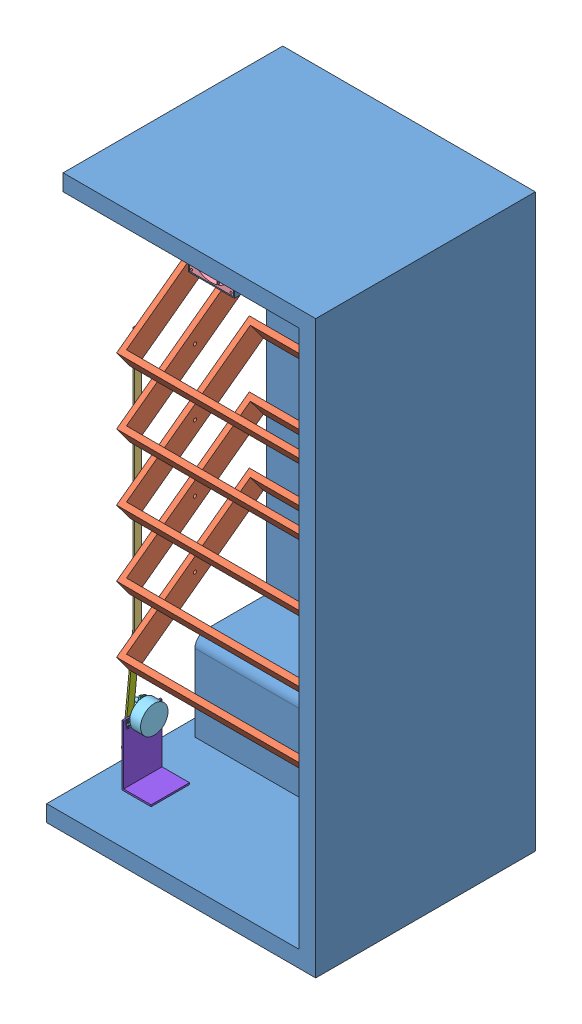
SolidWorks assembly lapgheptu2, configuration Default. Lengths in mm.
Overall size (490 1040 400).
12 component instances, 8 part files, 29 mates.
Components (placement in the parent):
- thungtu2-1: thungtu2 [Default] at (159.6175 470.8921 967.7159) size (490 1040 400)
- khaylat-1: khaylat [Default] at (164.6175 734.784 1115.8614) x (1 0 0) z (0 -0.592723 0.805406) size (410 40 300)
- khaylat-2: khaylat [Default] at (164.6175 614.784 1115.8614) x (1 0 0) z (0 -0.592723 0.805406) size (410 40 300)
- khaylat-3: khaylat [Default] at (164.6175 494.784 1115.8614) x (1 0 0) z (0 -0.592723 0.805406) size (410 40 300)
- khaylat-4: khaylat [Default] at (164.6175 374.784 1115.8614) x (1 0 0) z (0 -0.592723 0.805406) size (410 40 300)
- khaylat-5: khaylat [Default] at (164.6175 254.784 1115.8614) x (1 0 0) z (0 -0.592723 0.805406) size (410 40 300)
- caylap-1: caylap [Default] at (-43.3825 445.6926 1216.3106) size (3 500 12)
- khungquat-1: khungquat [Default] at (144.6175 920.8921 1242.7159) size (80 80 25)
- dongco-1: dongco [Default] at (-15.3825 85.8921 1211.7159) x (-1 0 0) z (0 0 -1) size (35 50 63.71)
- caylapdc-1: caylapdc [Default] at (-37.3825 67.8015 1223.1181) x (-1 0 0) z (0 -0.325777 -0.945447) size (13 90 12)
- caynoi-1: caynoi [Default] at (-45.3825 121.1472 1225.0896) x (1 0 0) z (0 0.103283 0.994652) size (3 190 12)
- gadedc-1: gadedc [Default] at (-35.3825 35.8921 1212.5572) x (0 0 1) z (-1 0 0) size (70 110 53)
Mates (geometry in assembly coordinates):
- Concentric1: concentric: cylinder of thungtu2-1 through (324.6175 750.8921 1127.7159) axis (1 0 0) radius 3; cylinder of ? through (-43.8678 750.8921 1127.7159) axis (1 0 0) radius 3
- Distance1: distance = 10 mm: plane of assembly; plane of assembly; plane of khaylat-1 through (364.6175 678.0918 1260.3813) normal (1 0 0); plane of thungtu2-1 through (374.6175 -19.1079 1337.7159) normal (-1 0 0)
- Concentric2: concentric: cylinder of thungtu2-1 through (324.6175 630.8921 1127.7159) axis (1 0 0) radius 3; cylinder of ? through (-43.8678 630.8921 1127.7159) axis (1 0 0) radius 3
- Distance2: distance = 10 mm: plane of assembly; plane of assembly; plane of khaylat-2 through (364.6175 558.0918 1260.3813) normal (1 0 0); plane of thungtu2-1 through (374.6175 -19.1079 1337.7159) normal (-1 0 0)
- Concentric3: concentric: cylinder of thungtu2-1 through (324.6175 510.8921 1127.7159) axis (1 0 0) radius 3; cylinder of ? through (-43.8678 510.8921 1127.7159) axis (1 0 0) radius 3
- Distance3: distance = 10 mm: plane of assembly; plane of assembly; plane of khaylat-3 through (364.6175 438.0918 1260.3813) normal (1 0 0); plane of thungtu2-1 through (374.6175 -19.1079 1337.7159) normal (-1 0 0)
- Concentric4: concentric: cylinder of thungtu2-1 through (324.6175 390.8921 1127.7159) axis (1 0 0) radius 3; cylinder of ? through (-43.8678 390.8921 1127.7159) axis (1 0 0) radius 3
- Distance4: distance = 10 mm: plane of assembly; plane of assembly; plane of khaylat-4 through (364.6175 318.0918 1260.3813) normal (1 0 0); plane of thungtu2-1 through (374.6175 -19.1079 1337.7159) normal (-1 0 0)
- Concentric5: concentric: cylinder of thungtu2-1 through (324.6175 270.8921 1127.7159) axis (1 0 0) radius 3; cylinder of ? through (-43.8678 270.8921 1127.7159) axis (1 0 0) radius 3
- Distance5: distance = 10 mm: plane of assembly; plane of assembly; plane of khaylat-5 through (364.6175 198.0918 1260.3813) normal (1 0 0); plane of thungtu2-1 through (374.6175 -19.1079 1337.7159) normal (-1 0 0)
- Coincident9: coincident: circle of ?; cylinder of ? through (-31.8972 718.3402 1253.5744) axis (-1 0 0) radius 3
- Distance6: distance = 5 mm: plane of assembly; plane of assembly; plane of khaylat-1 through (-35.3825 678.0918 1260.3813) normal (-1 0 0); plane of caylap-1 through (-40.3825 445.6926 1216.3106) normal (1 0 0)
- Coincident11: coincident: circle of ?; cylinder of ? through (-31.8972 598.3402 1253.5744) axis (-1 0 0) radius 3
- Coincident12: coincident: circle of ?; cylinder of ? through (-31.8972 478.3402 1253.5744) axis (-1 0 0) radius 3
- Coincident13: coincident: circle of ?; cylinder of ? through (-31.8972 358.3402 1253.5744) axis (-1 0 0) radius 3
- Coincident14: coincident: circle of ?; cylinder of ? through (-31.8972 238.3402 1253.5744) axis (-1 0 0) radius 3
- Coincident15: coincident: plane of assembly; plane of assembly; plane of thungtu2-1 through (-55.3825 960.8921 1337.7159) normal (0 -1 0); plane of khungquat-1 through (104.6175 960.8921 1263.7159) normal (0 1 0)
- Distance7: distance = 190 mm: plane of assembly; plane of assembly; plane of khungquat-1 through (184.6175 880.8921 1263.7159) normal (1 0 0); plane of thungtu2-1 through (374.6175 -19.1079 1337.7159) normal (-1 0 0)
- Coincident17: coincident: plane of assembly; plane of assembly; plane of thungtu2-1 through (159.6175 470.8921 1267.7159) normal (0 0 1); plane of khungquat-1 through (144.6175 920.8921 1267.7159) normal (0 0 1)
- Distance8: distance = 410 mm: plane of assembly; plane of assembly; plane of dongco-1 through (-35.3825 85.8921 1211.7159) normal (-1 0 0); plane of thungtu2-1 through (374.6175 -19.1079 1337.7159) normal (-1 0 0)
- Distance10: distance = 120 mm: plane of assembly; plane of assembly; plane of dongco-1 through (-48.3825 100.8921 1211.7159) normal (0 -1 0); plane of thungtu2-1 through (-55.3825 -19.1079 1337.7159) normal (0 1 0)
- Distance11: distance = 244 mm: plane of assembly; plane of assembly; plane of dongco-1 through (-48.3825 100.8921 1211.7159) normal (0 0 -1); plane of thungtu2-1 through (159.6175 470.8921 967.7159) normal (0 0 1)
- Concentric6: concentric: cylinder of dongco-1 through (-50.3825 100.8921 1211.7159) axis (1 0 0) radius 3.5; cylinder of ? through (-27.483 100.8921 1211.7159) axis (-1 0 0) radius 3.5
- Distance12: distance = 2 mm: plane of assembly; plane of assembly; plane of caylapdc-1 through (-37.3825 67.8015 1223.1181) normal (1 0 0); plane of dongco-1 through (-35.3825 85.8921 1211.7159) normal (-1 0 0)
- Distance13: distance = 2 mm: plane of assembly; plane of assembly; plane of caynoi-1 through (-42.3825 121.1472 1225.0896) normal (1 0 0); plane of caylapdc-1 through (-40.3825 67.8015 1223.1181) normal (-1 0 0)
- Coincident33: coincident: cylinder of ? through (-45.3825 243.3482 1234.2116) axis (1 0 0) radius 3; circle of ?
- Coincident34: coincident: circle of ?; cylinder of ? through (-33.8972 69.3363 1271.9507) axis (-1 0 0) radius 3
- Coincident35: coincident: plane of assembly; plane of assembly; plane of thungtu2-1 through (-55.3825 -19.1079 1337.7159) normal (0 1 0); plane of gadedc-1 through (-38.3825 -19.1079 1177.5572) normal (0 -1 0)
- Coincident36: coincident: plane of assembly; plane of assembly; plane of dongco-1 through (-35.3825 85.8921 1211.7159) normal (-1 0 0); plane of gadedc-1 through (-35.3825 35.8921 1212.5572) normal (1 0 0)
